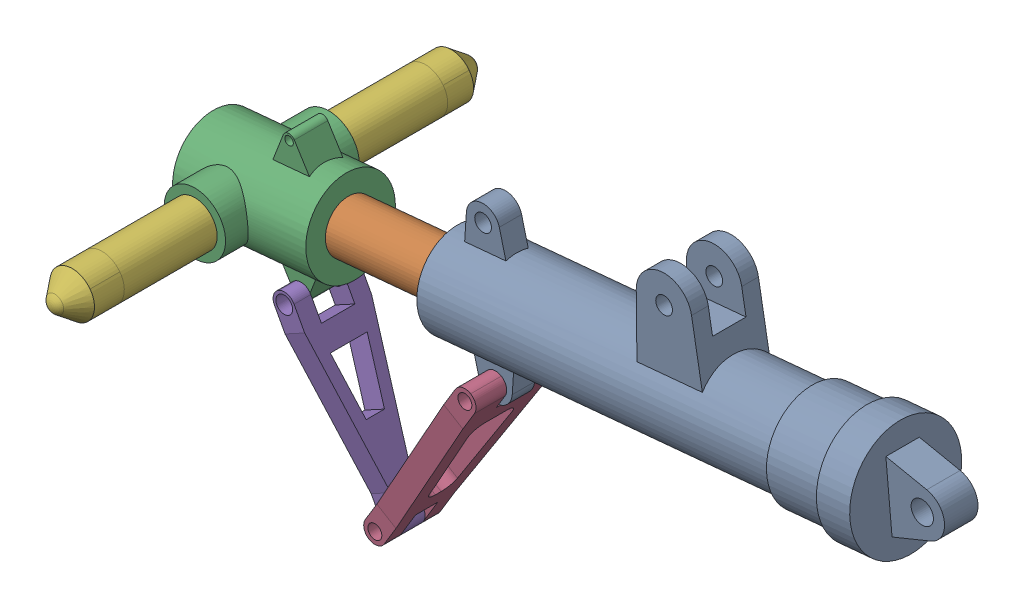
SolidWorks assembly landing_gear, configuration Default. Lengths in mm.
Overall size (679.94 370.58 378.75).
7 component instances, 6 part files, 11 mates.
Components (placement in the parent):
- oleostrut-1: oleostrut [Default] at (-204.26 4.1701 0) x (-0.092986 0.995667 0) z (0 0 -1) size (180 450 100)
- oleopiston-1: oleopiston [Default] at (-363.5668 -10.7076 0) x (0.09225 -0.987788 -0.125562) z (0.011675 -0.125018 0.992086) size (60 380 60)
- wheel_hub-1: wheel_hub [Default] at (-642.3537 -36.7436 0) x (-0.092986 0.995667 0) z (0 0 -1) size (126.18 120 120)
- upprsway_lnk-1: upprsway_lnk [Default] at (-491.4348 -100.7086 0) x (-0.517956 -0.855407 0) z (-0.855407 0.517956 0) size (200 75 20)
- lwrsway_lnk-1: lwrsway_lnk [Default] at (-627.7912 -180.204 -5) x (-0.476649 0.879094 0) z (0.879094 0.476649 0) size (180 60 20)
- wheelassy-1: wheelassy [Default] at (-636.3327 -111.0635 0.0257) x (0 0 1) z (0.667142 0.744931 0) size (378.75 40 40)
  - part3-1: part3 [Default] at origin size (378.75 40 40)
Mates (geometry in assembly coordinates):
- Concentric9: concentric aligned: cylinder of oleostrut-1 through (-104.6933 13.4686 0) axis (0.995667 0.092986 0) radius 40; cylinder of oleopiston-1 through (-273.9568 -2.3389 0) axis (0.995667 0.092986 0) radius 22.5
- Coincident11: coincident anti-aligned: plane of oleopiston-1 through (-650.2348 -59.8986 -2.8251) normal (-0.995667 -0.092986 0); plane of wheel_hub-1 through (-652.3104 -37.6734 0) normal (0.995667 0.092986 0)
- Concentric10: concentric aligned: cylinder of oleopiston-1 through (-273.9568 -2.3389 0) axis (0.995667 0.092986 0) radius 22.5; cylinder of wheel_hub-1 through (-652.3104 -37.6734 0) axis (0.995667 0.092986 0) radius 22.5
- Distance6: distance = 100 mm anti-aligned: plane of oleostrut-1 through (-534.9225 -4.1126 0) normal (-0.995667 -0.092986 0); plane of wheel_hub-1 through (-636.1165 4.013 0) normal (0.995667 0.092986 0)
- Coincident12: coincident anti-aligned: plane of oleostrut-1 through (-492.4028 -83.0007 -10) normal (0 0 -1); plane of upprsway_lnk-1 through (-508.7262 -90.6523 -10) normal (0 0 1)
- Concentric11: concentric aligned: cylinder of oleostrut-1 through (-492.4028 -83.0007 -10) axis (0 0 1) radius 7.5; cylinder of upprsway_lnk-1 through (-492.4028 -83.0007 -37.5) axis (0 0 1) radius 6.25
- Concentric13: concentric aligned: cylinder of wheel_hub-1 through (-661.8987 -96.3191 -15) axis (0 0 1) radius 3.8212; cylinder of lwrsway_lnk-1 through (-661.8987 -96.3191 -30) axis (0 0 1) radius 7.5
- Concentric15: concentric aligned: cylinder of upprsway_lnk-1 through (-585.6348 -236.974 -37.5) axis (0 0 1) radius 6.25; cylinder of lwrsway_lnk-1 through (-585.6348 -236.974 -30) axis (0 0 1) radius 7.5
- Coincident13: coincident anti-aligned: plane of upprsway_lnk-1 through (-599.3685 -240.3486 10) normal (0 0 -1); plane of lwrsway_lnk-1 through (-572.0774 -240.9985 10) normal (0 0 1)
- Concentric16: concentric anti-aligned: circle of wheel_hub-1; circle of wheelassy-1/part3-1
- Distance8: distance = 109.347 mm anti-aligned: plane of wheel_hub-1 through (-712.0504 -43.2526 -60) normal (0 0 -1); sphere of wheelassy-1/part3-1
